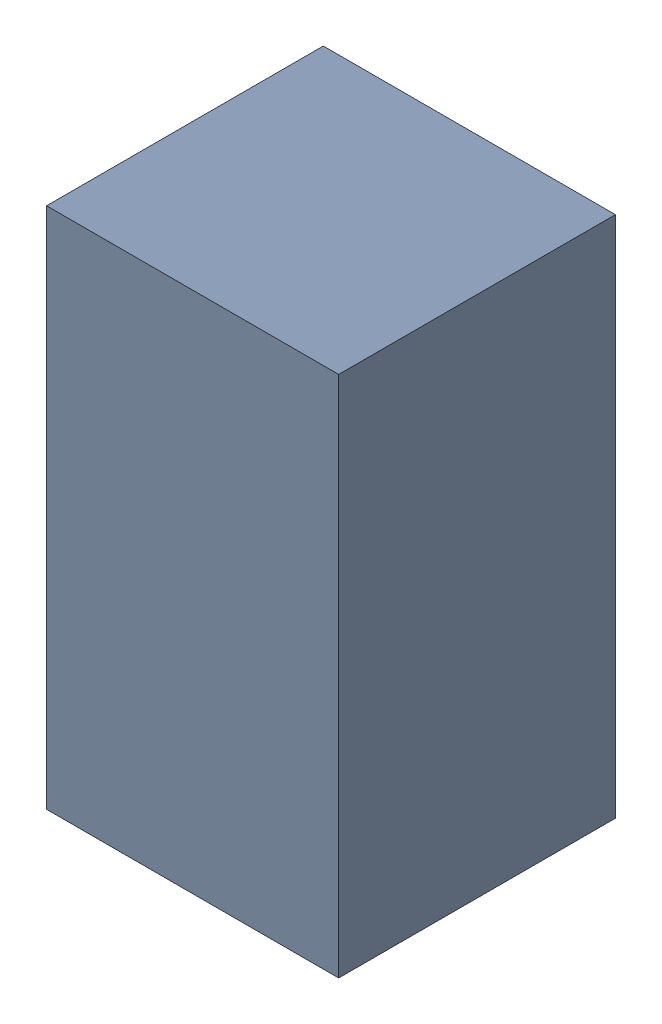
SolidWorks assembly R203, configuration Standard. Lengths in mm.
Overall size (0.95 1.7 0.9).
2 component instances, 1 part files, 0 mates.
Components (placement in the parent):
- 885541560-1: 885541560 [Standard] at (6.1 -13 0) size (0.95 1.7 0.9)
  - Extruded_16-1: Extruded_16 [Standard] at origin size (0.95 1.7 0.9)
